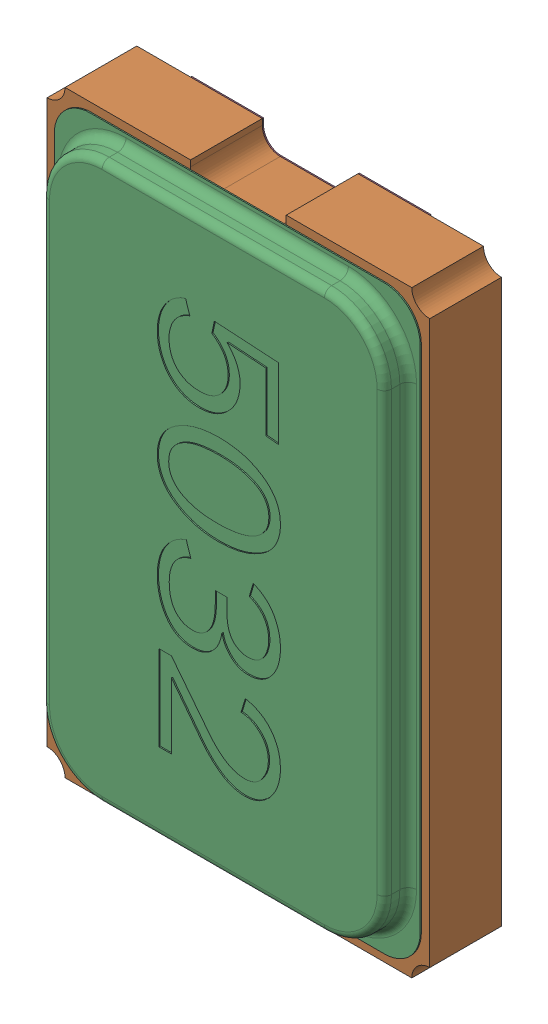
SolidWorks assembly OS2, configuration 默认. Lengths in mm.
Overall size (3.2 5 0.82).
3 component instances, 2 part files, 0 mates.
Components (placement in the parent):
- OSC_5032-2-1: OSC_5032-2 [默认] at (71.7044 82.8039 0) x (0 -1 0) z (0 0 1) size (5 3.2 0.82)
  - OSC_5032-2-1: OSC_5032-2 [默认] at origin size (5 3.2 0.82)
  - LOGO_0.5-1: LOGO_0.5 [默认] at (-0.0001 0.1135 0.045) size (1.5 1.73 0.01)
